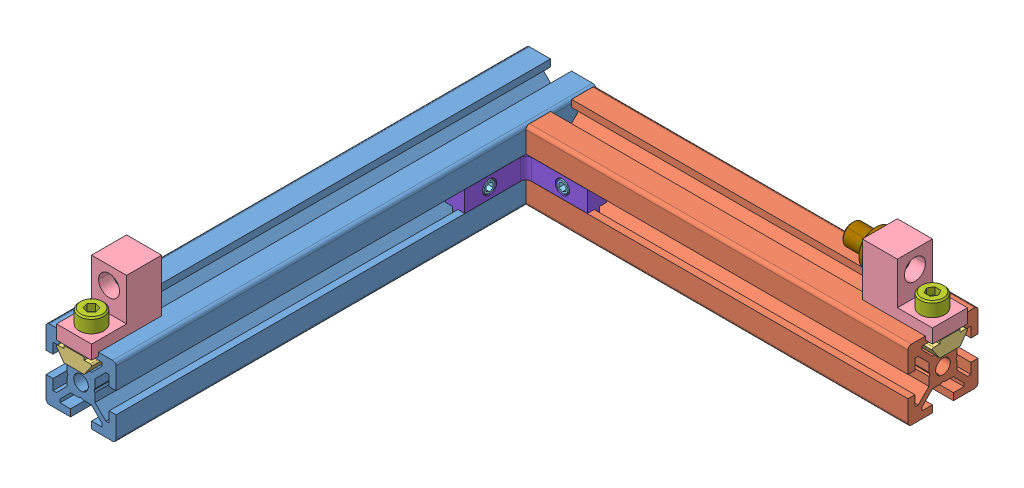
SolidWorks assembly 110303047-61, configuration 預設. Lengths in mm.
Overall size (131 36.99 139).
13 component instances, 9 part files, 27 mates.
Components (placement in the parent):
- HFS5-2020-137-2: HFS5-2020-137 [預設] at (99.4125 21.0825 164.5538) size (20 20 137)
- HFS5-2020-109-2: HFS5-2020-109 [預設] at (218.4125 21.0825 37.5538) x (0 0 -1) z (1 0 0) size (20 20 109)
- HNTTSN5-4-1: HNTTSN5-4 [預設] at (99.4125 29.8325 161.5538) x (0 1 0) z (0 0 1) size (4.3 10 10)
- revolute_support-1: revolute_support [Default] at (99.4125 41.0825 146.5538) x (-1 0 0) z (0 0 -1) size (10 16 20)
- revolute_support-2: revolute_support [Default] at (200.4125 41.0825 37.5538) x (0 0 1) z (-1 0 0) size (10 16 20)
- MSSFS4-5-1: MSSFS4-5 [預設] at (119.8014 21.0825 45.0538) x (0 0 -1) z (1 0 0) size (5 4 4)
- MSSFS4-5-2: MSSFS4-5 [預設] at (106.9125 21.0825 57.9427) x (-1 0 0) z (0 0 -1) size (5 4 4)
- MDZB6-6-1: MDZB6-6 [預設] at (99.4125 41.0825 152.5538) x (0 0 -1) z (0.500222 -0.865897 0) size (6 8 8)
- SCB4-8-1: SCB4-8 [預設] at (99.4125 34.0825 161.5538) x (0 -1 0) z (0.238793 0 -0.971071) size (12 7 7)
- SCB4-8-2: SCB4-8 [預設] at (215.4125 34.0825 37.5538) x (0 -1 0) z (-0.023758 0 0.999718) size (12 7 7)
- HBLBS5-1: HBLBS5 [預設] at (103.9125 21.0825 42.0538) x (1 0 0) z (0 -1 0) size (23 23 10)
- HNTTSN5-4-4: HNTTSN5-4 [預設] at (215.4125 29.8825 37.5538) x (0 1 0) z (1 0 0) size (4.3 10 10)
- revolute_joint-1: revolute_joint [預設] at (206.4125 41.0825 37.5538) x (0 0.593882 -0.804552) z (0 0.804552 0.593882) size (10 14 10)
Mates (geometry in assembly coordinates):
- 重合/共線/共點1: coincident aligned: plane of HFS5-2020-137-2 through (108.4125 31.0825 27.5538) normal (0 1 0); plane of HFS5-2020-109-2 through (109.4125 31.0825 40.5538) normal (0 1 0)
- 重合/共線/共點2: coincident anti-aligned: plane of HFS5-2020-137-2 through (109.4125 24.0825 27.5538) normal (1 0 0); plane of HFS5-2020-109-2 through (109.4125 12.0825 46.5538) normal (-1 0 0)
- 重合/共線/共點3: coincident aligned: plane of HFS5-2020-137-2 through (90.4125 12.0825 27.5538) normal (0 0 -1); plane of HFS5-2020-109-2 through (109.4125 24.0825 27.5538) normal (0 0 -1)
- 同軸心1: concentric aligned: cylinder of HNTTSN5-4-1 through (99.4125 29.8325 161.5538) axis (0 1 0) radius 1.621; cylinder of revolute_support-1 through (99.4125 29.0825 161.5538) axis (0 1 0) radius 2
- 輪廓中心1: profile center anti-aligned: circle of revolute_support-2; circle of SCB4-8-2
- 輪廓中心2: profile center anti-aligned: plane of revolute_support-1 through (104.4125 34.0825 166.5538) normal (0 1 0); circle of SCB4-8-1
- 同軸心6: concentric aligned: cylinder of revolute_support-1 through (99.4125 41.0825 166.5538) axis (0 0 -1) radius 3; cylinder of MDZB6-6-1 through (99.4125 41.0825 146.5538) axis (0 0 -1) radius 3
- 重合/共線/共點6: coincident aligned: plane of revolute_support-1 through (99.4125 41.0825 146.5538) normal (0 0 -1); plane of MDZB6-6-1 through (102.4431 42.8333 146.5538) normal (0 0 -1)
- 重合/共線/共點7: coincident anti-aligned: plane of HFS5-2020-137-2 through (107.4125 27.0825 27.5538) normal (-1 0 0); plane of HBLBS5-1 through (107.4125 16.0825 50.0538) normal (1 0 0)
- 同軸心7: concentric anti-aligned: cylinder of MSSFS4-5-1 through (119.8014 21.0825 42.5538) axis (0 0 -1) radius 2; cylinder of HBLBS5-1 through (119.8014 21.0825 47.5538) axis (0 0 1) radius 1.65
- 重合/共線/共點10: coincident aligned: plane of MSSFS4-5-1 through (119.8014 21.0825 47.5538) normal (0 0 1); plane of HBLBS5-1 through (126.9125 18.1325 47.5538) normal (0 0 1)
- 同軸心8: concentric anti-aligned: cylinder of MSSFS4-5-2 through (104.4125 21.0825 57.9427) axis (-1 0 0) radius 2; cylinder of HBLBS5-1 through (109.4125 21.0825 57.9427) axis (1 0 0) radius 1.65
- 重合/共線/共點11: coincident aligned: plane of MSSFS4-5-2 through (109.4125 21.0825 57.9427) normal (1 0 0); plane of HBLBS5-1 through (109.4125 18.1325 47.5538) normal (1 0 0)
- 寬度3: width anti-aligned: plane of HBLBS5-1 through (103.9125 24.0325 42.0538) normal (0 1 0); plane of HFS5-2020-137-2 through (103.9125 18.1325 42.0538) normal (0 -1 0); plane of HBLBS5-1 through (107.4125 24.0825 27.5538) normal (0 -1 0); plane of HFS5-2020-137-2 through (109.4125 18.0825 27.5538) normal (0 1 0)
- 寬度2: width aligned: plane of HNTTSN5-4-1 through (96.5125 29.6325 166.5538) normal (-1 0 0); plane of HFS5-2020-137-2 through (102.3125 29.0325 166.5538) normal (1 0 0); plane of HNTTSN5-4-1 through (102.4125 31.0825 27.5538) normal (-1 0 0); plane of HFS5-2020-137-2 through (96.4125 29.0825 27.5538) normal (1 0 0)
- 平行4: parallel: line of HFS5-2020-137-2 through (102.4125 31.0825 27.5538) axis (0 0 1); plane of revolute_support-1 through (104.4125 46.0825 166.5538) normal (1 0 0)
- 平行5: parallel aligned: plane of revolute_support-2 through (220.4125 46.0825 32.5538) normal (0 0 -1); line of HFS5-2020-109-2 through (109.4125 31.0825 34.5538) axis (1 0 0)
- 重合/共線/共點23: coincident aligned: plane of HFS5-2020-109-2 through (109.4125 30.0825 47.5538) normal (0 0 1); plane of HBLBS5-1 through (126.9125 18.1325 47.5538) normal (0 0 1)
- 重合/共線/共點24: coincident anti-aligned: plane of HFS5-2020-137-2 through (108.4125 31.0825 27.5538) normal (0 1 0); plane of revolute_support-1 through (104.4125 31.0825 146.5538) normal (0 -1 0)
- 重合/共線/共點25: coincident anti-aligned: plane of HFS5-2020-137-2 through (90.4125 12.0825 164.5538) normal (0 0 1); plane of revolute_support-1 through (104.4125 31.0825 164.5538) normal (0 0 -1)
- 重合/共線/共點26: coincident anti-aligned: plane of HFS5-2020-109-2 through (109.4125 31.0825 40.5538) normal (0 1 0); plane of revolute_support-2 through (200.4125 31.0825 32.5538) normal (0 -1 0)
- 同軸心11: concentric anti-aligned: cylinder of SCB4-8-2 through (215.4125 26.0825 37.5538) axis (0 -1 0) radius 2; cylinder of HNTTSN5-4-4 through (215.4125 29.8825 37.5538) axis (0 1 0) radius 1.621
- 重合/共線/共點27: coincident anti-aligned: plane of HFS5-2020-109-2 through (218.4125 12.0825 46.5538) normal (1 0 0); plane of revolute_support-2 through (218.4125 31.0825 32.5538) normal (-1 0 0)
- 寬度1: width anti-aligned: plane of HNTTSN5-4-4 through (220.4125 29.6825 40.4538) normal (0 0 1); plane of HFS5-2020-109-2 through (220.4125 29.0825 34.6538) normal (0 0 -1); plane of HNTTSN5-4-4 through (109.4125 29.0825 40.5538) normal (0 0 -1); plane of HFS5-2020-109-2 through (109.4125 31.0825 34.5538) normal (0 0 1)
- 重合/共線/共點28: coincident anti-aligned: plane of HFS5-2020-109-2 through (109.4125 29.0825 43.5538) normal (0 -1 0); plane of HNTTSN5-4-4 through (220.4125 29.0825 40.4538) normal (0 1 0)
- 重合/共線/共點30: coincident anti-aligned: plane of revolute_support-2 through (200.4125 41.0825 37.5538) normal (-1 0 0); plane of revolute_joint-1 through (200.4125 38.1131 41.5765) normal (1 0 0)
- 同軸心13: concentric aligned: cylinder of revolute_support-2 through (206.4125 41.0825 37.5538) axis (-1 0 0) radius 4; cylinder of revolute_joint-1 through (206.4125 41.0825 37.5538) axis (-1 0 0) radius 4
